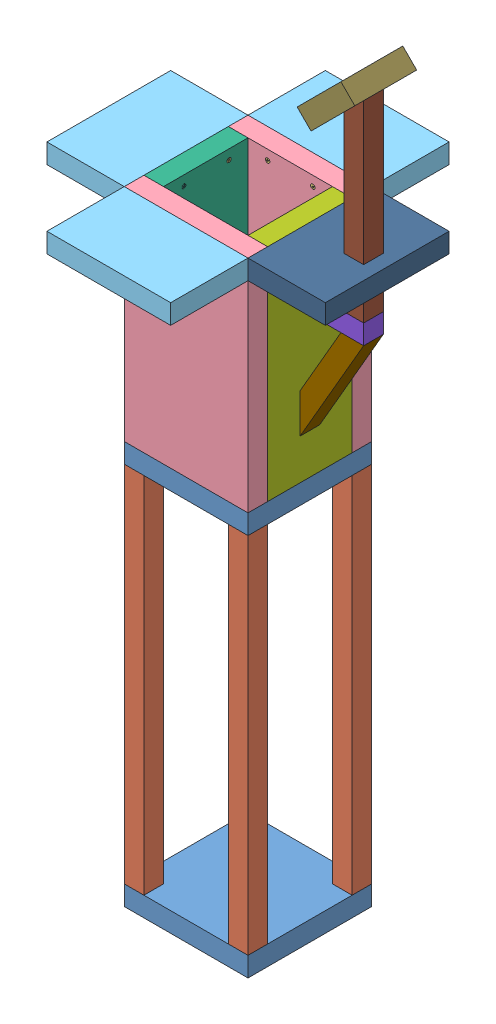
SolidWorks assembly Drop tower holder, configuration Default. Lengths in mm.
Overall size (360 1023.4 360).
50 component instances, 12 part files, 33 mates.
Components (placement in the parent):
- Base tile-1: Base tile [Default] at origin size (160 25.4 160)
- helical holder-1: helical holder [Default] at (67.3 260.4 67.3) size (25.4 470 25.4)
- helical holder-2: helical holder [Default] at (-67.3 260.4 67.3) x (0 0 1) z (-1 0 0) size (25.4 470 25.4)
- helical holder-3: helical holder [Default] at (-67.3 260.4 -67.3) x (-1 0 0) z (0 0 -1) size (25.4 470 25.4)
- helical holder-4: helical holder [Default] at (67.3 260.4 -67.3) x (0 0 -1) z (1 0 0) size (25.4 470 25.4)
- Base tile-2: Base tile [top tile] at (0 520.8 0) x (-1 0 0) z (0 0 1) size (160 25.4 160)
- 90031A117_PHILLIPS FLAT HEAD SCREWS FOR WOOD-1: 90031A117_PHILLIPS FLAT HEAD SCREWS FOR WOOD [90031A117] at (-67.3 15.875 -67.3) x (0 1 0) z (-0.546944 0 0.837169) size (31.75 5.71 5.71)
- 90031A117_PHILLIPS FLAT HEAD SCREWS FOR WOOD-2: 90031A117_PHILLIPS FLAT HEAD SCREWS FOR WOOD [90031A117] at (67.3 15.875 -67.3) x (0 1 0) z (-0.837169 0 -0.546944) size (31.75 5.71 5.71)
- 90031A117_PHILLIPS FLAT HEAD SCREWS FOR WOOD-3: 90031A117_PHILLIPS FLAT HEAD SCREWS FOR WOOD [90031A117] at (67.3 15.875 67.3) x (0 1 0) z (0.546944 0 -0.837169) size (31.75 5.71 5.71)
- 90031A117_PHILLIPS FLAT HEAD SCREWS FOR WOOD-4: 90031A117_PHILLIPS FLAT HEAD SCREWS FOR WOOD [90031A117] at (-67.3 15.875 67.3) x (0 1 0) z (0.837169 0 0.546944) size (31.75 5.71 5.71)
- 90031A117_PHILLIPS FLAT HEAD SCREWS FOR WOOD-5: 90031A117_PHILLIPS FLAT HEAD SCREWS FOR WOOD [90031A117] at (-67.3 504.925 -67.3) x (0 -1 0) z (-0.546944 0 0.837169) size (31.75 5.71 5.71)
- 90031A117_PHILLIPS FLAT HEAD SCREWS FOR WOOD-6: 90031A117_PHILLIPS FLAT HEAD SCREWS FOR WOOD [90031A117] at (67.3 504.925 -67.3) x (0 -1 0) z (-0.837169 0 -0.546944) size (31.75 5.71 5.71)
- 90031A117_PHILLIPS FLAT HEAD SCREWS FOR WOOD-7: 90031A117_PHILLIPS FLAT HEAD SCREWS FOR WOOD [90031A117] at (67.3 504.925 67.3) x (0 -1 0) z (0.546944 0 -0.837169) size (31.75 5.71 5.71)
- 90031A117_PHILLIPS FLAT HEAD SCREWS FOR WOOD-8: 90031A117_PHILLIPS FLAT HEAD SCREWS FOR WOOD [90031A117] at (-67.3 504.925 67.3) x (0 -1 0) z (0.837169 0 0.546944) size (31.75 5.71 5.71)
- 90031A117_PHILLIPS FLAT HEAD SCREWS FOR WOOD-9: 90031A117_PHILLIPS FLAT HEAD SCREWS FOR WOOD [90031A117] at (67.3005 511.2241 29.2) x (0 1 0) z (0 0 1) size (31.75 5.71 5.71)
- 90031A117_PHILLIPS FLAT HEAD SCREWS FOR WOOD-10: 90031A117_PHILLIPS FLAT HEAD SCREWS FOR WOOD [90031A117] at (67.3005 511.2241 -29.2) x (0 1 0) z (0 0 1) size (31.75 5.71 5.71)
- 90031A117_PHILLIPS FLAT HEAD SCREWS FOR WOOD-11: 90031A117_PHILLIPS FLAT HEAD SCREWS FOR WOOD [90031A117] at (-67.3005 511.275 29.2) x (0 1 0) z (-0.546944 0 0.837169) size (31.75 5.71 5.71)
- 90031A117_PHILLIPS FLAT HEAD SCREWS FOR WOOD-12: 90031A117_PHILLIPS FLAT HEAD SCREWS FOR WOOD [90031A117] at (-67.3005 511.275 -29.2) x (0 1 0) z (-0.546944 0 0.837169) size (31.75 5.71 5.71) (hidden)
- long side-3: long side [Default] at (0 663.5 54.6) x (0 -1 0) z (-1 0 0) size (285.4 25.4 160)
- 90031A117_PHILLIPS FLAT HEAD SCREWS FOR WOOD-13: 90031A117_PHILLIPS FLAT HEAD SCREWS FOR WOOD [90031A117] at (29.2 511.275 67.3005) x (0 1 0) z (-0.546944 0 0.837169) size (31.75 5.71 5.71) (hidden)
- 90031A117_PHILLIPS FLAT HEAD SCREWS FOR WOOD-14: 90031A117_PHILLIPS FLAT HEAD SCREWS FOR WOOD [90031A117] at (-29.2 511.275 67.3005) x (0 1 0) z (-0.546944 0 0.837169) size (31.75 5.71 5.71) (hidden)
- long side-4: long side [Default] at (0 663.5 -54.6) x (0 -1 0) z (1 0 0) size (285.4 25.4 160)
- 90031A117_PHILLIPS FLAT HEAD SCREWS FOR WOOD-15: 90031A117_PHILLIPS FLAT HEAD SCREWS FOR WOOD [90031A117] at (29.2 511.275 -67.3005) x (0 1 0) z (-0.546944 0 0.837169) size (31.75 5.71 5.71)
- 90031A117_PHILLIPS FLAT HEAD SCREWS FOR WOOD-16: 90031A117_PHILLIPS FLAT HEAD SCREWS FOR WOOD [90031A117] at (-29.2 511.275 -67.3005) x (0 1 0) z (-0.546944 0 0.837169) size (31.75 5.71 5.71)
- antenna protector-1: antenna protector [Default] at (0 780.8 -130) x (0 0 1) z (-1 0 0) size (100 25.4 160)
- 90031A117_PHILLIPS FLAT HEAD SCREWS FOR WOOD-17: 90031A117_PHILLIPS FLAT HEAD SCREWS FOR WOOD [90031A117] at (-29.2 793.5 -70.475) x (0 0 -1) z (0.92358 0.383406 0) size (31.75 5.71 5.71)
- 90031A117_PHILLIPS FLAT HEAD SCREWS FOR WOOD-18: 90031A117_PHILLIPS FLAT HEAD SCREWS FOR WOOD [90031A117] at (29.2 793.5 -70.475) x (0 0 -1) z (0.92358 0.383406 0) size (31.75 5.71 5.71)
- antenna protector-2: antenna protector [Default] at (0 780.8 130) x (0 0 -1) z (1 0 0) size (100 25.4 160)
- 90031A117_PHILLIPS FLAT HEAD SCREWS FOR WOOD-19: 90031A117_PHILLIPS FLAT HEAD SCREWS FOR WOOD [90031A117] at (29.2 793.5 70.475) x (0 0 1) z (-0.923874 -0.382697 0) size (31.75 5.71 5.71)
- 90031A117_PHILLIPS FLAT HEAD SCREWS FOR WOOD-20: 90031A117_PHILLIPS FLAT HEAD SCREWS FOR WOOD [90031A117] at (-29.2 793.5 70.475) x (0 0 1) z (-0.923874 -0.382697 0) size (31.75 5.71 5.71)
- small side-1: small side [Default] at (-80 663.5 0) x (0 -1 0) z (0 0 1) size (285.4 25.4 109.2)
- 90031A117_PHILLIPS FLAT HEAD SCREWS FOR WOOD-21: 90031A117_PHILLIPS FLAT HEAD SCREWS FOR WOOD [90031A117] at (-67.3 793.5 -64.125) x (0 0 1) z (-1 0 0) size (31.75 5.71 5.71)
- 90031A117_PHILLIPS FLAT HEAD SCREWS FOR WOOD-22: 90031A117_PHILLIPS FLAT HEAD SCREWS FOR WOOD [90031A117] at (-67.3 793.5 64.125) x (0 0 -1) z (-1 0 0) size (31.75 5.71 5.71)
- 90031A117_PHILLIPS FLAT HEAD SCREWS FOR WOOD-23: 90031A117_PHILLIPS FLAT HEAD SCREWS FOR WOOD [90031A117] at (67.3 793.5 -64.125) x (0 0 1) z (-1 0 0) size (31.75 5.71 5.71)
- 90031A117_PHILLIPS FLAT HEAD SCREWS FOR WOOD-24: 90031A117_PHILLIPS FLAT HEAD SCREWS FOR WOOD [90031A117] at (67.3 793.5 64.125) x (0 0 -1) z (-1 0 0) size (31.75 5.71 5.71)
- antenna protector-3: antenna protector [Default] at (-130 780.8 0) size (100 25.4 160)
- 90031A117_PHILLIPS FLAT HEAD SCREWS FOR WOOD-27: 90031A117_PHILLIPS FLAT HEAD SCREWS FOR WOOD [90031A117] at (-78.6119 793.5 28.4) x (-1 0 0) z (0 -0.443974 -0.89604) size (31.75 5.71 5.71) (hidden)
- 90031A117_PHILLIPS FLAT HEAD SCREWS FOR WOOD-28: 90031A117_PHILLIPS FLAT HEAD SCREWS FOR WOOD [90031A117] at (-70.475 793.5 -30) x (-1 0 0) z (0 -0.322506 -0.946567) size (31.75 5.71 5.71)
- mounting-1: mounting [Default] at (-75.2195 747.9409 -235.0864) x (0 -1 0) z (0 0 1) size (502.6 125.4 160)
  - small side with mount-1: small side with mount [Default] at (84.4409 129.8195 235.0864) size (285.4 25.4 109.2)
  - a side of triangle-1: a side of triangle [Default] at (32.483 196.3149 235.0864) x (0 1 0) z (0 0 1) size (82.19 25.4 25.4)
  - hypothonuse-2: hypothonuse [Default] at (174.8409 155.2195 235.0864) x (0 0 1) z (0 -1 0) size (25.4 142.36 82.19)
  - antenna protector with mount-1: antenna protector with mount [Default] at (-58.2591 205.2195 235.0864) x (0 -1 0) z (0 0 1) size (100 25.4 160)
  - tall mount-1: tall mount [Default] at (-117.402 224.7099 235.0864) x (0 -1 0) z (0 0 -1) size (25.4 248.97 25.4)
  - mount top-1: mount top [Default] at (-229.2119 224.7348 234.7909) x (0 0 1) z (0.707107 -0.707107 0) size (80 25.4 80)
  - 90031A117_PHILLIPS FLAT HEAD SCREWS FOR WOOD-1: 90031A117_PHILLIPS FLAT HEAD SCREWS FOR WOOD [90031A117] at (-235.6146 217.6671 234.7681) x (0.707107 0.707107 0) z (0 0 1) size (31.75 5.71 5.71)
  - 90031A117_PHILLIPS FLAT HEAD SCREWS FOR WOOD-2: 90031A117_PHILLIPS FLAT HEAD SCREWS FOR WOOD [90031A117] at (19.6301 145.6945 235.0326) x (0 1 0) z (-0.546944 0 0.837169) size (31.75 5.71 5.71)
  - 90031A117_PHILLIPS FLAT HEAD SCREWS FOR WOOD-3: 90031A117_PHILLIPS FLAT HEAD SCREWS FOR WOOD [90031A117] at (149.6575 145.6945 235.1226) x (0 1 0) z (-0.546944 0 0.837169) size (31.75 5.71 5.71)
  - 90031A117_PHILLIPS FLAT HEAD SCREWS FOR WOOD-6: 90031A117_PHILLIPS FLAT HEAD SCREWS FOR WOOD [90031A117] at (-45.5591 145.6945 264.2864) x (0 1 0) z (-0.546944 0 0.837169) size (31.75 5.71 5.71)
  - 90031A117_PHILLIPS FLAT HEAD SCREWS FOR WOOD-7: 90031A117_PHILLIPS FLAT HEAD SCREWS FOR WOOD [90031A117] at (-45.5591 145.6945 205.8864) x (0 1 0) z (-0.546944 0 0.837169) size (31.75 5.71 5.71)
Mates (geometry in assembly coordinates):
- Coincident1: coincident: plane of Base tile-1 through (0 25.4 0) normal (0 1 0); plane of helical holder-1 through (67.3 25.4 67.3) normal (0 -1 0)
- Concentric2: concentric: cylinder of Base tile-1 through (67.3 0 67.3) axis (0 -1 0) radius 0.8065; cylinder of helical holder-1 through (67.3 25.4 67.3) axis (0 -1 0) radius 0.8065
- Coincident2: coincident: plane of helical holder-2 through (-67.3 495.4 67.3) normal (0 1 0); plane of Base tile-2 through (0 495.4 0) normal (0 -1 0)
- Concentric3: concentric: circle of helical holder-3; circle of Base tile-2
- Concentric7: concentric: cylinder of Base tile-2 through (67.3 520.8 -67.3) axis (0 1 0) radius 0.8065; cylinder of helical holder-4 through (67.3 495.4 -67.3) axis (0 1 0) radius 0.8065
- Concentric8: concentric: circle of Base tile-1; cylinder of 90031A117_PHILLIPS FLAT HEAD SCREWS FOR WOOD-1 through (-67.3 0 -67.3) axis (0 -1 0) radius 1.4224
- Coincident6: coincident: plane of Base tile-1 through (0 0 0) normal (0 -1 0); plane of 90031A117_PHILLIPS FLAT HEAD SCREWS FOR WOOD-1 through (-67.3 0 -67.3) normal (0 -1 0)
- Coincident12: coincident: circle of Base tile-2; circle of 90031A117_PHILLIPS FLAT HEAD SCREWS FOR WOOD-13
- Coincident13: coincident: cone of Base tile-2 through (-29.2 495.4 67.3005) axis (0 1 0); circle of 90031A117_PHILLIPS FLAT HEAD SCREWS FOR WOOD-14
- Coincident16: coincident: circle of Base tile-2; circle of 90031A117_PHILLIPS FLAT HEAD SCREWS FOR WOOD-16
- Coincident17: coincident: plane of long side-4 through (0 663.5 -80) normal (0 0 -1); plane of antenna protector-1 through (80 806.2 -80) normal (0 0 1)
- Coincident18: coincident: circle of long side-4; circle of 90031A117_PHILLIPS FLAT HEAD SCREWS FOR WOOD-17
- Coincident19: coincident: circle of long side-4; circle of 90031A117_PHILLIPS FLAT HEAD SCREWS FOR WOOD-18
- Coincident20: coincident: circle of long side-3; circle of 90031A117_PHILLIPS FLAT HEAD SCREWS FOR WOOD-19
- Coincident21: coincident: circle of long side-3; circle of 90031A117_PHILLIPS FLAT HEAD SCREWS FOR WOOD-20
- Coincident30: coincident: circle of long side-4; circle of 90031A117_PHILLIPS FLAT HEAD SCREWS FOR WOOD-21
- Coincident31: coincident: circle of long side-4; circle of 90031A117_PHILLIPS FLAT HEAD SCREWS FOR WOOD-23
- Concentric24: concentric: circle of small side-1; circle of 90031A117_PHILLIPS FLAT HEAD SCREWS FOR WOOD-27
- Concentric25: concentric: circle of small side-1; circle of 90031A117_PHILLIPS FLAT HEAD SCREWS FOR WOOD-27
- Concentric26: concentric: circle of small side-1; circle of 90031A117_PHILLIPS FLAT HEAD SCREWS FOR WOOD-28
- Coincident47: coincident: plane of long side-4 through (-80 806.2 -80) normal (0 1 0); plane of antenna protector-1 through (0 806.2 -130) normal (0 1 0)
- Coincident48: coincident: plane of long side-4 through (-80 806.2 -80) normal (-1 0 0); plane of antenna protector-1 through (-80 806.2 -180) normal (-1 0 0)
- Concentric29: concentric: cylinder of small side-1 through (-54.6 793.5 28.4) axis (1 0 0) radius 0.889; cylinder of antenna protector-3 through (-80 793.5 28.4) axis (1 0 0) radius 0.889
- Coincident57: coincident: plane of Base tile-2 through (0 520.8 0) normal (0 1 0); plane of long side-3 through (80 520.8 80) normal (0 -1 0)
- Coincident61: coincident: plane of long side-3 through (-80 806.2 80) normal (-1 0 0); plane of Base tile-2 through (-80 495.4 80) normal (-1 0 0)
- Coincident62: coincident: plane of Base tile-2 through (80 495.4 80) normal (0 0 1); plane of long side-3 through (0 663.5 80) normal (0 0 1)
- Coincident68: coincident: plane of small side-1 through (-54.6 806.2 -54.6) normal (0 1 0); plane of antenna protector-3 through (-130 806.2 0) normal (0 1 0)
- Coincident70: coincident: plane of long side-4 through (-80 806.2 -80) normal (-1 0 0); plane of antenna protector-3 through (-80 806.2 -80) normal (1 0 0)
- Coincident71: coincident: circle of small side-1; plane of 90031A117_PHILLIPS FLAT HEAD SCREWS FOR WOOD-28 through (-54.6 793.5 -30) normal (1 0 0)
- Coincident72: coincident: plane of long side-4 through (0 663.5 -54.6) normal (0 0 1); plane of small side-1 through (-54.6 806.2 -54.6) normal (0 0 -1)
- Coincident73: coincident: line of Base tile-2 through (-80 520.8 80) axis (0 0 -1); line of small side-1 through (-80 520.8 54.6) axis (0 0 -1)
- Coincident74: coincident: line of Base tile-2 through (80 520.8 -80) axis (0 0 1); line of mounting-1/small side with mount-1 through (80 520.8 54.6) axis (0 0 -1)
- Coincident75: coincident: line of long side-3 through (80 520.8 54.6) axis (0 1 0); line of mounting-1/small side with mount-1 through (80 806.2 54.6) axis (0 -1 0)
